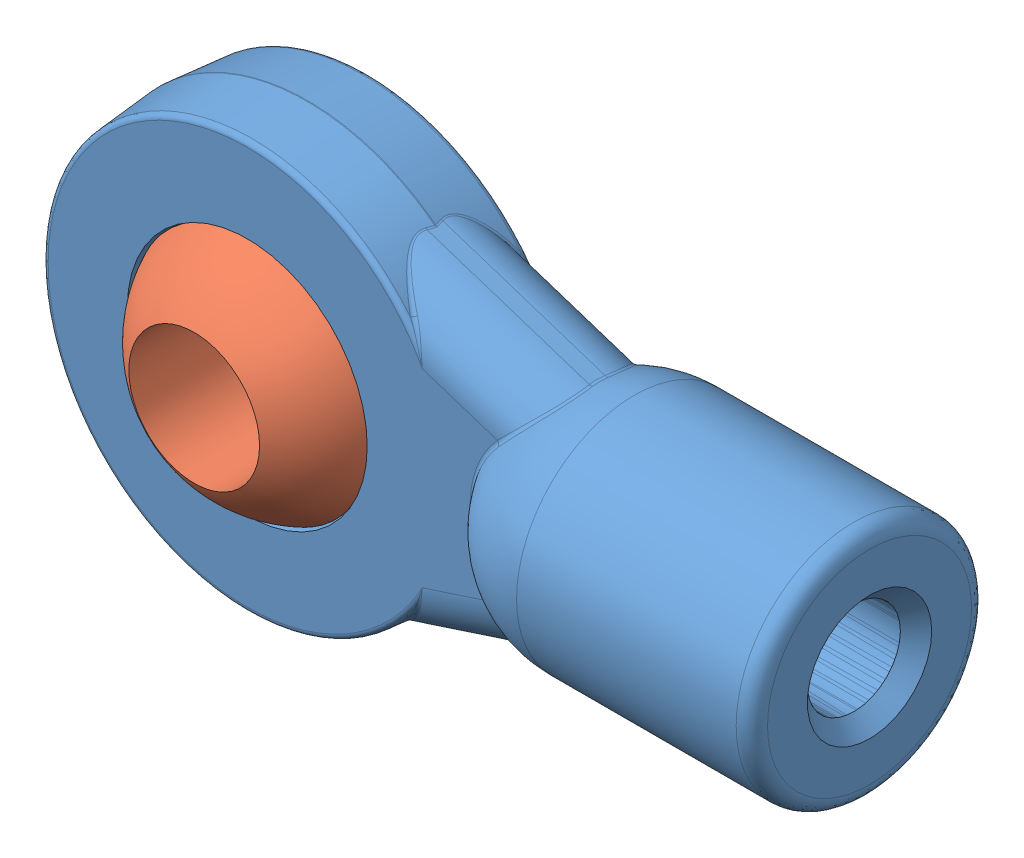
SolidWorks assembly Ball end assem, configuration Default. Lengths in mm.
Overall size (18.73 10.16 5.71).
2 component instances, 2 part files, 1 mates.
Components (placement in the parent):
- Ball End-1: Ball End [Default] at origin size (18.73 10.16 5.71)
- 0.025 Ball-1: 0.025 Ball [Default] at origin size (6.35 6.35 5.5)
Mates (geometry in assembly coordinates):
- Coincident1: coordinate: point of 0.025 Ball-1
